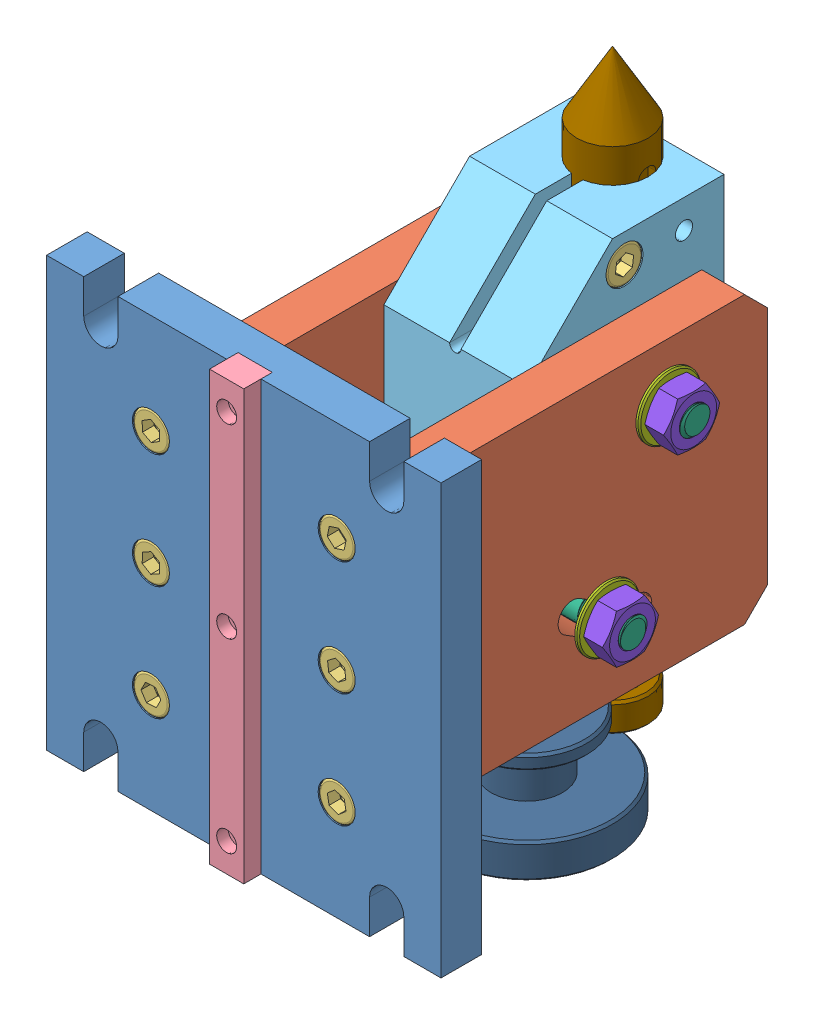
SolidWorks assembly Ensamblaje Punto, configuration Predeterminado. Lengths in mm.
Overall size (138 217 150).
25 component instances, 11 part files, 52 mates.
Components (placement in the parent):
- Elemento 60 Base punto--1: Elemento 60 Base punto- [Predeterminado] at origin size (138 150 14.2)
- Elemento 52 Lateral punto.-1: Elemento 52 Lateral punto. [Predeterminado] at (40 0 -64.5) x (0 0 1) z (-1 0 0) size (129 100 15)
- Elemento 52 Lateral punto.-2: Elemento 52 Lateral punto. [Predeterminado] at (-25 0 -64.5) x (0 0 1) z (-1 0 0) size (129 100 15)
- socket head cap screw_din-7: socket head cap screw_din [DIN 912 M8 x 25 --- 25N] at (32.5 -40 14.2) x (0 0 -1) z (0.338143 0.941095 0) size (33 13 13)
- socket head cap screw_din-8: socket head cap screw_din [DIN 912 M8 x 25 --- 25N] at (32.5 0 14.2) x (0 0 -1) z (0.992882 0.119099 0) size (33 13 13)
- socket head cap screw_din-9: socket head cap screw_din [DIN 912 M8 x 25 --- 25N] at (-32.5 -40 14.2) x (0 0 -1) z (-0.892203 0.451634 0) size (33 13 13)
- socket head cap screw_din-10: socket head cap screw_din [DIN 912 M8 x 25 --- 25N] at (-32.5 0 14.2) x (0 0 -1) z (0.484607 -0.874732 0) size (33 13 13)
- socket head cap screw_din-11: socket head cap screw_din [DIN 912 M8 x 25 --- 25N] at (-32.5 40 14.2) x (0 0 -1) z (-0.528458 0.848959 0) size (33 13 13)
- socket head cap screw_din-12: socket head cap screw_din [DIN 912 M8 x 25 --- 25N] at (32.5 40 14.2) x (0 0 -1) z (0.979919 -0.199394 0) size (33 13 13)
- Elemento 53 Guia del punto.-1: Elemento 53 Guia del punto. [Predeterminado] at (0 0 10.2) size (12 150 10)
- Elemento 53 Guia del contrapunto.-1: Elemento 53 Guia del contrapunto. [Predeterminado] at (0 75 -129.8) x (0 -1 0) z (1 0 0) size (125 70 50)
- socket head cap screw_din-13: socket head cap screw_din [DIN 912 M8 x 40 --- 28N] at (25 65 -94) x (-1 0 0) z (0 -0.924225 -0.381849) size (48 13 13)
- Elemento 55 Esparrago contrapunto.-1: Elemento 55 Esparrago contrapunto. [Predeterminado] at (-50 30 -94) x (0 0.422146 -0.906528) z (1 0 0) size (10.26 10 101.48)
- Elemento 55 Esparrago contrapunto.-2: Elemento 55 Esparrago contrapunto. [Predeterminado] at (50 -23.6 -72.6) x (0 0 1) z (-1 0 0) size (10.26 10 101.48)
- Elemento 56 Arandela M-10-1: Elemento 56 Arandela M-10 [Predeterminado] at (41.2 -23.6 -72.6) x (0 0 1) z (-1 0 0) size (22 22 1.2)
- Elemento 56 Arandela M-10-2: Elemento 56 Arandela M-10 [Predeterminado] at (41.2 30 -94) x (0 0 1) z (-1 0 0) size (22 22 1.2)
- Elemento 56 Arandela M-10-3: Elemento 56 Arandela M-10 [Predeterminado] at (-41.2 30 -94) x (0 0 -1) z (1 0 0) size (22 22 1.2)
- Elemento 56 Arandela M-10-4: Elemento 56 Arandela M-10 [Predeterminado] at (-41.2 -23.6 -72.6) x (0 0 -1) z (1 0 0) size (22 22 1.2)
- Elemento 57 Tierca M-10-1: Elemento 57 Tierca M-10 [Default] at (-49.2 30 -94) x (0 0 -1) z (1 0 0) size (19.63 17 8)
- Elemento 57 Tierca M-10-2: Elemento 57 Tierca M-10 [Default] at (-49.2 -23.6 -72.6) x (0 0 -1) z (1 0 0) size (19.63 17 8)
- Elemento 57 Tierca M-10-3: Elemento 57 Tierca M-10 [Default] at (49.2 30 -94) x (0 0 1) z (-1 0 0) size (19.63 17 8)
- Elemento 57 Tierca M-10-4: Elemento 57 Tierca M-10 [Default] at (49.2 -23.6 -72.6) x (0 0 1) z (-1 0 0) size (19.63 17 8)
- Elemento 58 Punto.-1: Elemento 58 Punto. [Predeterminado] at (0 -91.6106 -114.8) x (0 0 -1) z (1 0 0) size (25 200 25)
- Elemento 60 Tuerca de ajuste.-1: Elemento 60 Tuerca de ajuste. [Predeterminado] at (0 -108.6106 -84.8) x (0.982492 0 0.186307) z (-0.186307 0 0.982492) size (60 32 60)
- Elemento 59 Husillo punto--1: Elemento 59 Husillo punto- [Predeterminado] at (0 -108.6106 -84.8) size (10.02 84.95 10.26)
Mates (geometry in assembly coordinates):
- Coincidente5: coincident anti-aligned: plane of Elemento 60 Base punto--1 through (-50 -63 0) normal (0 0 -1); plane of Elemento 52 Lateral punto.-1 through (25 -50 0) normal (0 0 1)
- Coincidente6: coincident anti-aligned: plane of Elemento 60 Base punto--1 through (-50 -63 0) normal (0 0 -1); plane of Elemento 52 Lateral punto.-2 through (-40 -50 0) normal (0 0 1)
- Concéntrica5: concentric aligned: cylinder of Elemento 60 Base punto--1 through (32.5 -40 6.2) axis (0 0 1) radius 6.5; cylinder of Elemento 52 Lateral punto.-1 through (32.5 -40 0) axis (0 0 1) radius 3.4
- Concéntrica6: concentric aligned: cylinder of Elemento 60 Base punto--1 through (32.5 40 6.2) axis (0 0 1) radius 6.5; cylinder of Elemento 52 Lateral punto.-1 through (32.5 40 0) axis (0 0 1) radius 3.4
- Concéntrica7: concentric aligned: cylinder of Elemento 60 Base punto--1 through (-32.5 -40 6.2) axis (0 0 1) radius 6.5; cylinder of Elemento 52 Lateral punto.-2 through (-32.5 -40 0) axis (0 0 1) radius 3.4
- Concéntrica8: concentric aligned: cylinder of Elemento 60 Base punto--1 through (-32.5 40 6.2) axis (0 0 1) radius 6.5; cylinder of Elemento 52 Lateral punto.-2 through (-32.5 40 0) axis (0 0 1) radius 3.4
- Concéntrica15: concentric aligned: cylinder of Elemento 60 Base punto--1 through (32.5 -40 6.2) axis (0 0 1) radius 6.5; cylinder of socket head cap screw_din.sldprt1-7 through (32.5 -40 45.95) axis (0 0 1) radius 4
- Concéntrica16: concentric aligned: cylinder of Elemento 60 Base punto--1 through (32.5 0 6.2) axis (0 0 1) radius 6.5; cylinder of socket head cap screw_din.sldprt1-8 through (32.5 0 45.95) axis (0 0 1) radius 4
- Concéntrica17: concentric aligned: cylinder of Elemento 60 Base punto--1 through (32.5 40 6.2) axis (0 0 1) radius 6.5; cylinder of socket head cap screw_din.sldprt1-12 through (32.5 40 45.95) axis (0 0 1) radius 4
- Concéntrica18: concentric aligned: cylinder of Elemento 60 Base punto--1 through (-32.5 40 6.2) axis (0 0 1) radius 6.5; cylinder of socket head cap screw_din.sldprt1-11 through (-32.5 40 45.95) axis (0 0 1) radius 4
- Concéntrica19: concentric aligned: cylinder of Elemento 60 Base punto--1 through (-32.5 0 6.2) axis (0 0 1) radius 6.5; cylinder of socket head cap screw_din.sldprt1-10 through (-32.5 0 45.95) axis (0 0 1) radius 4
- Concéntrica20: concentric aligned: cylinder of Elemento 60 Base punto--1 through (-32.5 -40 6.2) axis (0 0 1) radius 6.5; cylinder of socket head cap screw_din.sldprt1-9 through (-32.5 -40 45.95) axis (0 0 1) radius 4
- Coincidente12: coincident anti-aligned: plane of Elemento 60 Base punto--1 through (32.5 40 6.2) normal (0 0 1); plane of socket head cap screw_din.sldprt1-12 through (33.7961 46.3695 6.2) normal (0 0 -1)
- Coincidente13: coincident aligned: plane of Elemento 60 Base punto--1 through (-50 -63 14.2) normal (0 0 1); plane of socket head cap screw_din.sldprt1-8 through (32.5 0 14.2) normal (0 0 1)
- Coincidente14: coincident aligned: plane of Elemento 60 Base punto--1 through (-50 -63 14.2) normal (0 0 1); plane of socket head cap screw_din.sldprt1-7 through (32.5 -40 14.2) normal (0 0 1)
- Coincidente15: coincident aligned: plane of Elemento 60 Base punto--1 through (-50 -63 14.2) normal (0 0 1); plane of socket head cap screw_din.sldprt1-10 through (-32.5 0 14.2) normal (0 0 1)
- Coincidente16: coincident aligned: plane of Elemento 60 Base punto--1 through (-50 -63 14.2) normal (0 0 1); plane of socket head cap screw_din.sldprt1-11 through (-32.5 40 14.2) normal (0 0 1)
- Coincidente17: coincident aligned: plane of Elemento 60 Base punto--1 through (-50 -63 14.2) normal (0 0 1); plane of socket head cap screw_din.sldprt1-9 through (-32.5 -40 14.2) normal (0 0 1)
- Coincidente18: coincident anti-aligned: plane of Elemento 60 Base punto--1 through (-6 -81.994 10.2) normal (0 0 1); plane of Elemento 53 Guia del punto.-1 through (-6 75 10.2) normal (0 0 -1)
- Coincidente19: coincident anti-aligned: plane of Elemento 60 Base punto--1 through (6 80.3173 10.2) normal (-1 0 0); plane of Elemento 53 Guia del punto.-1 through (6 -75 20.2) normal (1 0 0)
- Concéntrica21: concentric anti-aligned: cylinder of Elemento 60 Base punto--1 through (0 -65 14.2) axis (0 0 -1) radius 2; cylinder of Elemento 53 Guia del punto.-1 through (0 -65 16.2) axis (0 0 1) radius 3.5
- Coincidente24: coincident anti-aligned: plane of Elemento 52 Lateral punto.-1 through (25 50 0) normal (-1 0 0); plane of Elemento 53 Guia del contrapunto.-1 through (25 75 -129.8) normal (1 0 0)
- Concéntrica24: concentric anti-aligned: cylinder of Elemento 52 Lateral punto.-1 through (25 30 -94) axis (1 0 0) radius 5; cylinder of Elemento 53 Guia del contrapunto.-1 through (25 30 -94) axis (-1 0 0) radius 5
- Paralelo1: parallel aligned: plane of Elemento 52 Lateral punto.-1 through (25 -42 -129) normal (0 0 -1); plane of Elemento 53 Guia del contrapunto.-1 through (25 75 -129.8) normal (0 0 -1)
- Concéntrica26: concentric aligned: cylinder of Elemento 53 Guia del contrapunto.-1 through (17 65 -94) axis (1 0 0) radius 6.5; cylinder of socket head cap screw_din.sldprt1-13 through (56.75 65 -94) axis (1 0 0) radius 4
- Coincidente27: coincident aligned: plane of Elemento 53 Guia del contrapunto.-1 through (25 75 -129.8) normal (1 0 0); plane of socket head cap screw_din.sldprt1-13 through (25 65 -94) normal (1 0 0)
- Concéntrica27: concentric anti-aligned: cylinder of Elemento 52 Lateral punto.-1 through (25 30 -94) axis (1 0 0) radius 5; cylinder of Elemento 55 Esparrago contrapunto.-1 through (-35 30 -94) axis (-1 0 0) radius 5
- Distancia1: distance = 10 mm aligned: plane of Elemento 55 Esparrago contrapunto.-1 through (50 30 -94) normal (1 0 0); plane of Elemento 52 Lateral punto.-1 through (40 50 0) normal (1 0 0)
- Concéntrica28: concentric anti-aligned: cylinder of Elemento 53 Guia del contrapunto.-1 through (25 -23.6 -72.6) axis (-1 0 0) radius 5; cylinder of Elemento 55 Esparrago contrapunto.-2 through (35 -23.6 -72.6) axis (1 0 0) radius 5
- Distancia2: distance = 10 mm aligned: plane of Elemento 55 Esparrago contrapunto.-2 through (50 -23.6 -72.6) normal (1 0 0); plane of Elemento 52 Lateral punto.-1 through (40 50 0) normal (1 0 0)
- Concéntrica30: concentric aligned: cylinder of Elemento 55 Esparrago contrapunto.-2 through (35 -23.6 -72.6) axis (1 0 0) radius 5; cylinder of Elemento 56 Arandela M-10-4 through (-41.2 -23.6 -72.6) axis (1 0 0) radius 5.25
- Coincidente30: coincident anti-aligned: plane of Elemento 52 Lateral punto.-2 through (-40 50 0) normal (-1 0 0); plane of Elemento 56 Arandela M-10-4 through (-40 -23.6 -77.85) normal (1 0 0)
- Concéntrica31: concentric anti-aligned: cylinder of Elemento 55 Esparrago contrapunto.-1 through (-35 30 -94) axis (-1 0 0) radius 5; cylinder of Elemento 56 Arandela M-10-3 through (-41.2 30 -94) axis (1 0 0) radius 5.25
- Concéntrica32: concentric anti-aligned: cylinder of Elemento 56 Arandela M-10-2 through (41.2 30 -94) axis (-1 0 0) radius 5.25; cylinder of Elemento 56 Arandela M-10-3 through (-41.2 30 -94) axis (1 0 0) radius 5.25
- Concéntrica33: concentric anti-aligned: cylinder of Elemento 56 Arandela M-10-1 through (41.2 -23.6 -72.6) axis (-1 0 0) radius 5.25; cylinder of Elemento 56 Arandela M-10-4 through (-41.2 -23.6 -72.6) axis (1 0 0) radius 11
- Coincidente31: coincident anti-aligned: plane of Elemento 52 Lateral punto.-1 through (40 50 0) normal (1 0 0); plane of Elemento 56 Arandela M-10-1 through (40 -23.6 -67.35) normal (-1 0 0)
- Coincidente32: coincident anti-aligned: plane of Elemento 52 Lateral punto.-1 through (40 50 0) normal (1 0 0); plane of Elemento 56 Arandela M-10-2 through (40 30 -88.75) normal (-1 0 0)
- Coincidente33: coincident anti-aligned: plane of Elemento 52 Lateral punto.-2 through (-40 50 0) normal (-1 0 0); plane of Elemento 56 Arandela M-10-3 through (-40 30 -99.25) normal (1 0 0)
- Concéntrica34: concentric anti-aligned: cylinder of Elemento 56 Arandela M-10-2 through (41.2 30 -94) axis (-1 0 0) radius 11; cylinder of Elemento 57 Tierca M-10-3 through (49.2 30 -94) axis (1 0 0) radius 4.1881
- Coincidente34: coincident anti-aligned: plane of Elemento 56 Arandela M-10-2 through (41.2 30 -83) normal (1 0 0); plane of Elemento 57 Tierca M-10-3 through (41.2 30 -84.1851) normal (-1 0 0)
- Concéntrica35: concentric anti-aligned: cylinder of Elemento 56 Arandela M-10-1 through (41.2 -23.6 -72.6) axis (-1 0 0) radius 11; cylinder of Elemento 57 Tierca M-10-4 through (49.2 -23.6 -72.6) axis (1 0 0) radius 4.1881
- Coincidente35: coincident anti-aligned: plane of Elemento 56 Arandela M-10-1 through (41.2 -23.6 -61.6) normal (1 0 0); plane of Elemento 57 Tierca M-10-4 through (41.2 -23.6 -62.785) normal (-1 0 0)
- Concéntrica36: concentric anti-aligned: cylinder of Elemento 56 Arandela M-10-3 through (-41.2 30 -94) axis (1 0 0) radius 11; cylinder of Elemento 57 Tierca M-10-1 through (-49.2 30 -94) axis (-1 0 0) radius 4.1881
- Concéntrica37: concentric anti-aligned: cylinder of Elemento 56 Arandela M-10-4 through (-41.2 -23.6 -72.6) axis (1 0 0) radius 11; cylinder of Elemento 57 Tierca M-10-2 through (-49.2 -23.6 -72.6) axis (-1 0 0) radius 4.1881
- Coincidente36: coincident anti-aligned: plane of Elemento 56 Arandela M-10-4 through (-41.2 -23.6 -83.6) normal (-1 0 0); plane of Elemento 57 Tierca M-10-2 through (-41.2 -23.6 -82.415) normal (1 0 0)
- Coincidente37: coincident anti-aligned: plane of Elemento 56 Arandela M-10-3 through (-41.2 30 -105) normal (-1 0 0); plane of Elemento 57 Tierca M-10-1 through (-41.2 30 -103.8149) normal (1 0 0)
- Concéntrica38: concentric anti-aligned: cylinder of Elemento 53 Guia del contrapunto.-1 through (0 91.5 -114.8) axis (0 -1 0) radius 12.5; cylinder of Elemento 58 Punto.-1 through (0 108.3894 -114.8) axis (0 1 0) radius 12.5
- Coincidente39: coincident aligned: plane of Elemento 58 Punto.-1 through (0 -91.6106 -114.8) normal (1 0 0); plane of assembly through (0 0 0) normal (1 0 0)
- Concéntrica40: concentric anti-aligned: cylinder of Elemento 53 Guia del contrapunto.-1 through (0 -50 -84.8) axis (0 -1 0) radius 4.5; cylinder of Elemento 60 Tuerca de ajuste.-1 through (0 67.1931 -84.8) axis (0 1 0) radius 30
- Coincidente40: coincident anti-aligned: plane of Elemento 58 Punto.-1 through (0 -76.6106 -106.3) normal (0 -1 0); plane of Elemento 60 Tuerca de ajuste.-1 through (19.8463 -76.6106 -81.0366) normal (0 1 0)
- Concéntrica41: concentric anti-aligned: cylinder of Elemento 60 Tuerca de ajuste.-1 through (0 67.1931 -84.8) axis (0 1 0) radius 30; cylinder of Elemento 59 Husillo punto--1 through (0 -76.6106 -84.8) axis (0 -1 0) radius 4
- Coincidente41: coincident aligned: plane of Elemento 60 Tuerca de ajuste.-1 through (3.93 -108.6106 -84.0548) normal (0 -1 0); plane of Elemento 59 Husillo punto--1 through (0 -108.6106 -84.8) normal (0 -1 0)
